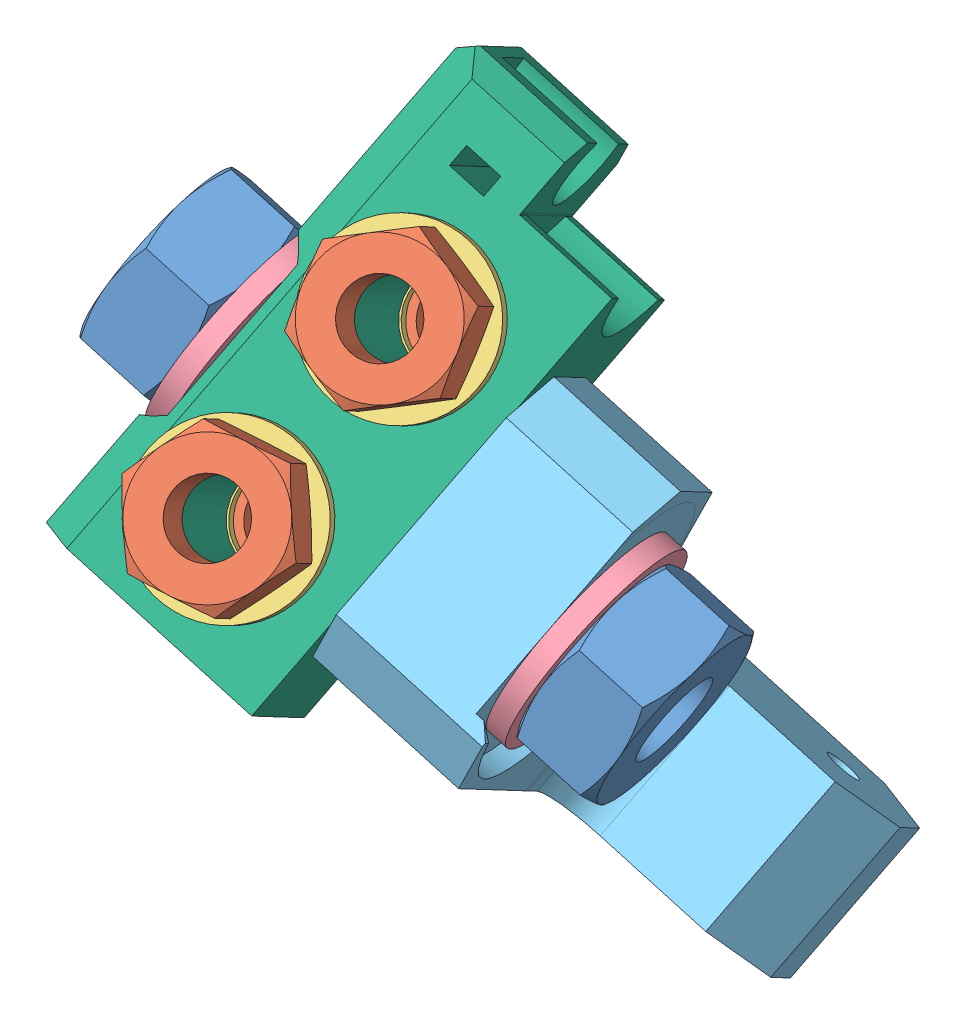
SolidWorks assembly Assembly y-corners + psu-y-part, configuration Valor predeterminado. Lengths in mm.
Overall size (70.09 85.08 72.81).
14 component instances, 6 part files, 27 mates.
Components (placement in the parent):
- Nut DIN 934 - M10-1: Nut DIN 934 - M10 [Valor predeterminado] at (19.9318 -6.7829 71.4778) x (0.883972 -0.4431 -0.149183) z (0.050052 -0.227561 0.972477) size (8 17 19.63)
- Nut DIN 934 - M8-1: Nut DIN 934 - M8 [Valor predeterminado] at (36.4951 -12.4723 85.973) x (-0.405972 -0.569176 -0.715) z (0.913882 -0.250711 -0.319317) size (6.5 13 15.01)
- Washer DIN 125A - M8-1: Washer DIN 125A - M8 [Valor predeterminado] at (39.1642 -1.3807 68.8448) x (0.405972 0.569176 0.715) z (-0.302013 -0.65486 0.692782) size (1.6 16 16)
- Washer DIN 125A - M10-2: Washer DIN 125A - M10 [Valor predeterminado] at (23.4677 -8.5553 70.881) x (0.883972 -0.4431 -0.149183) z (0.236023 0.147481 0.960491) size (2 20 20)
- Washer DIN 125A - M8-2: Washer DIN 125A - M8 [Valor predeterminado] at (35.1757 -14.3221 83.6493) x (-0.405972 -0.569176 -0.715) z (0.797091 0.162168 -0.581677) size (1.6 16 16)
- Washer DIN 125A - M8-3: Washer DIN 125A - M8 [Valor predeterminado] at (26.5691 -26.3887 68.4913) x (0.405972 0.569176 0.715) z (-0.845418 -0.063223 0.530351) size (1.6 16 16)
- Washer DIN 125A - M8-4: Washer DIN 125A - M8 [Valor predeterminado] at (31.8567 -11.6259 55.9748) x (-0.405972 -0.569176 -0.715) z (0.900505 -0.11575 -0.419157) size (1.6 16 16)
- Nut DIN 934 - M8-2: Nut DIN 934 - M8 [Valor predeterminado] at (25.2496 -28.2385 66.1675) x (0.405972 0.569176 0.715) z (-0.843078 0.535209 0.05264) size (6.5 13 15.01)
- Nut DIN 934 - M8-3: Nut DIN 934 - M8 [Valor predeterminado] at (29.8877 -14.3864 52.5071) x (-0.405972 -0.569176 -0.715) z (-0.398683 0.814303 -0.421857) size (6.5 13 15.01)
- Nut DIN 934 - M8-4: Nut DIN 934 - M8 [Valor predeterminado] at (41.1332 1.3798 72.3126) x (0.405972 0.569176 0.715) z (-0.820941 0.570893 0.011664) size (6.5 13 15.01)
- psu-y-part-1: psu-y-part [Valor predeterminado] at (45.8824 -41.1595 65.9269) x (-0.405972 -0.569176 -0.715) z (0.231905 0.692604 -0.683022) size (53 38 28)
- Nut DIN 934 - M10-3: Nut DIN 934 - M10 [Valor predeterminado] at (59.7106 -26.7224 64.7645) x (0.883972 -0.4431 -0.149183) z (-0.416609 -0.601685 -0.681478) size (8 17 19.63)
- Washer DIN 125A - M10-3: Washer DIN 125A - M10 [Valor predeterminado] at (54.4067 -24.0638 65.6596) x (0.883972 -0.4431 -0.149183) z (0.315015 0.800244 -0.51027) size (2 20 20)
- y-corners-3: y-corners [Valor predeterminado] at (38.277 -32.1555 81.2595) x (0.405972 0.569176 0.715) z (0.231905 0.692604 -0.683022) size (18 22 49)
Mates (geometry in assembly coordinates):
- Coincidente4: coincident: plane of ? through (28.1473 1.431 57.8379) normal (0.883972 -0.4431 -0.149183); plane of ? through (22.8511 -9.9405 71.3415) normal (-0.883972 0.4431 0.149183)
- Coincidente11: coincident: plane of ? through (44.1557 -20.38 83.3728) normal (-0.405972 -0.569176 -0.715); plane of ? through (51.0149 -22.2617 80.9761) normal (0.405972 0.569176 0.715)
- Coincidente12: coincident: plane of ? through (42.4083 -34.3283 65.8181) normal (-0.405972 -0.569176 -0.715); plane of ? through (48.7361 -38.3453 65.4231) normal (0.405972 0.569176 0.715)
- Coincidente13: coincident: plane of ? through (55.653 -8.4096 67.3157) normal (0.405972 0.569176 0.715); plane of ? through (61.8147 -12.6945 67.2282) normal (-0.405972 -0.569176 -0.715)
- Coincidente14: coincident: plane of ? through (47.0464 -20.4762 52.1577) normal (-0.405972 -0.569176 -0.715); plane of ? through (50.0388 -26.588 55.324) normal (0.405972 0.569176 0.715)
- Concêntrico15: concentric: cylinder of ? through (57.8704 -25.8 65.0751) axis (0.883972 -0.4431 -0.149183) radius 5.2; cylinder of ? through (72.014 -32.8896 62.6882) axis (-0.883972 0.4431 0.149183) radius 5.25
- Coincidente24: coincident: plane of ? through (70.246 -32.0034 62.9865) normal (0.883972 -0.4431 -0.149183); plane of ? through (70.246 -32.0034 62.9865) normal (-0.883972 0.4431 0.149183)
- Concêntrico16: concentric: cylinder of ? through (57.8704 -25.8 65.0751) axis (0.883972 -0.4431 -0.149183) radius 5.2; cylinder of ? through (79.0857 -36.4344 61.4947) axis (-0.883972 0.4431 0.149183) radius 4.25
- Coincidente25: coincident: plane of ? through (76.3438 -29.68 78.8112) normal (-0.883972 0.4431 0.149183); plane of ? through (72.014 -32.8896 62.6882) normal (0.883972 -0.4431 -0.149183)
- Concêntrico17: concentric: cylinder of ? through (55.653 -8.4096 67.3157) axis (-0.405972 -0.569176 -0.715) radius 4.2; cylinder of ? through (58.2919 -4.71 71.9632) axis (-0.405972 -0.569176 -0.715) radius 3.4
- Concêntrico18: concentric: cylinder of ? through (47.0464 -20.4762 52.1577) axis (0.405972 0.569176 0.715) radius 4.2; cylinder of ? through (44.4076 -24.1758 47.5102) axis (0.405972 0.569176 0.715) radius 3.4
- Concêntrico21: concentric: cylinder of ? through (43.0579 -33.4176 66.9621) axis (-0.405972 -0.569176 -0.715) radius 4.2; cylinder of ? through (42.4083 -34.3283 65.8181) axis (-0.405972 -0.569176 -0.715) radius 3.4
- Concêntrico22: concentric: cylinder of ? through (51.0149 -22.2617 80.9761) axis (0.405972 0.569176 0.715) radius 3.4; cylinder of ? through (50.3654 -23.1724 79.8321) axis (0.405972 0.569176 0.715) radius 4.2
- Concêntrico25: concentric: cylinder of ? through (24.9329 -9.2897 70.6338) axis (-0.883972 0.4431 0.149183) radius 4.25; cylinder of ? through (24.619 -10.8267 71.0431) axis (-0.883972 0.4431 0.149183) radius 5.25
- Concêntrico26: concentric: cylinder of assembly; cylinder of assembly; cylinder of Nut DIN 934 - M8-3 through (28.5683 -16.2362 50.1833) axis (0.405972 0.569176 0.715) radius 3.4; cylinder of y-corners-3 through (29.0149 -15.6101 50.9698) axis (0.405972 0.569176 0.715) radius 4.4
- Coincidente26: coincident: plane of assembly; plane of assembly; plane of Washer DIN 125A - M8-4 through (31.8567 -11.6259 55.9748) normal (0.405972 0.569176 0.715); plane of y-corners-3 through (15.1759 -27.5299 78.1065) normal (-0.405972 -0.569176 -0.715)
- Concêntrico27: concentric: cylinder of assembly; cylinder of assembly; cylinder of Nut DIN 934 - M8-2 through (26.5691 -26.3887 68.4913) axis (-0.405972 -0.569176 -0.715) radius 3.4; cylinder of y-corners-3 through (24.3768 -29.4622 64.6303) axis (0.405972 0.569176 0.715) radius 4.4
- Coincidente27: coincident: plane of assembly; plane of assembly; plane of Washer DIN 125A - M8-3 through (27.2186 -25.478 69.6353) normal (0.405972 0.569176 0.715); plane of y-corners-3 through (15.1759 -27.5299 78.1065) normal (-0.405972 -0.569176 -0.715)
- Concêntrico28: concentric: cylinder of assembly; cylinder of assembly; cylinder of Nut DIN 934 - M8-4 through (42.4526 3.2296 74.6363) axis (-0.405972 -0.569176 -0.715) radius 3.4; cylinder of y-corners-3 through (29.0149 -15.6101 50.9698) axis (0.405972 0.569176 0.715) radius 4.4
- Coincidente28: coincident: plane of assembly; plane of assembly; plane of Washer DIN 125A - M8-1 through (39.1642 -1.3807 68.8448) normal (-0.405972 -0.569176 -0.715); plane of y-corners-3 through (22.4834 -17.2848 90.9765) normal (0.405972 0.569176 0.715)
- Concêntrico29: concentric: cylinder of assembly; cylinder of assembly; cylinder of Nut DIN 934 - M8-1 through (35.1757 -14.3221 83.6493) axis (0.405972 0.569176 0.715) radius 3.4; cylinder of y-corners-3 through (24.3768 -29.4622 64.6303) axis (0.405972 0.569176 0.715) radius 4.4
- Coincidente29: coincident: plane of assembly; plane of assembly; plane of Washer DIN 125A - M8-2 through (34.5261 -15.2328 82.5053) normal (-0.405972 -0.569176 -0.715); plane of y-corners-3 through (22.4834 -17.2848 90.9765) normal (0.405972 0.569176 0.715)
- Concêntrico30: concentric: cylinder of assembly; cylinder of assembly; cylinder of psu-y-part-1 through (42.0311 -17.8604 67.7482) axis (0.883972 -0.4431 -0.149183) radius 5.2; cylinder of y-corners-3 through (19.0478 -6.3398 71.627) axis (0.883972 -0.4431 -0.149183) radius 5.4
- Coincidente30: coincident: plane of assembly; plane of assembly; plane of psu-y-part-1 through (43.9022 -22.4316 85.7094) normal (-0.883972 0.4431 0.149183); plane of y-corners-3 through (34.6233 -37.2781 74.8245) normal (0.883972 -0.4431 -0.149183)
- Paralelo1: parallel: plane of assembly; plane of assembly; plane of psu-y-part-1 through (56.9877 -28.9547 82.0736) normal (-0.231905 -0.692604 0.683022); plane of y-corners-3 through (15.1759 -27.5299 78.1065) normal (-0.231905 -0.692604 0.683022)
- Concêntrico31: concentric: cylinder of assembly; cylinder of assembly; cylinder of Nut DIN 934 - M10-1 through (23.4677 -8.5553 70.881) axis (-0.883972 0.4431 0.149183) radius 4.25; cylinder of y-corners-3 through (19.0478 -6.3398 71.627) axis (0.883972 -0.4431 -0.149183) radius 5.4
- Coincidente32: coincident: plane of assembly; plane of assembly; plane of Washer DIN 125A - M10-2 through (25.2356 -9.4415 70.5827) normal (0.883972 -0.4431 -0.149183); plane of y-corners-3 through (25.2356 -9.4415 70.5827) normal (-0.883972 0.4431 0.149183)
